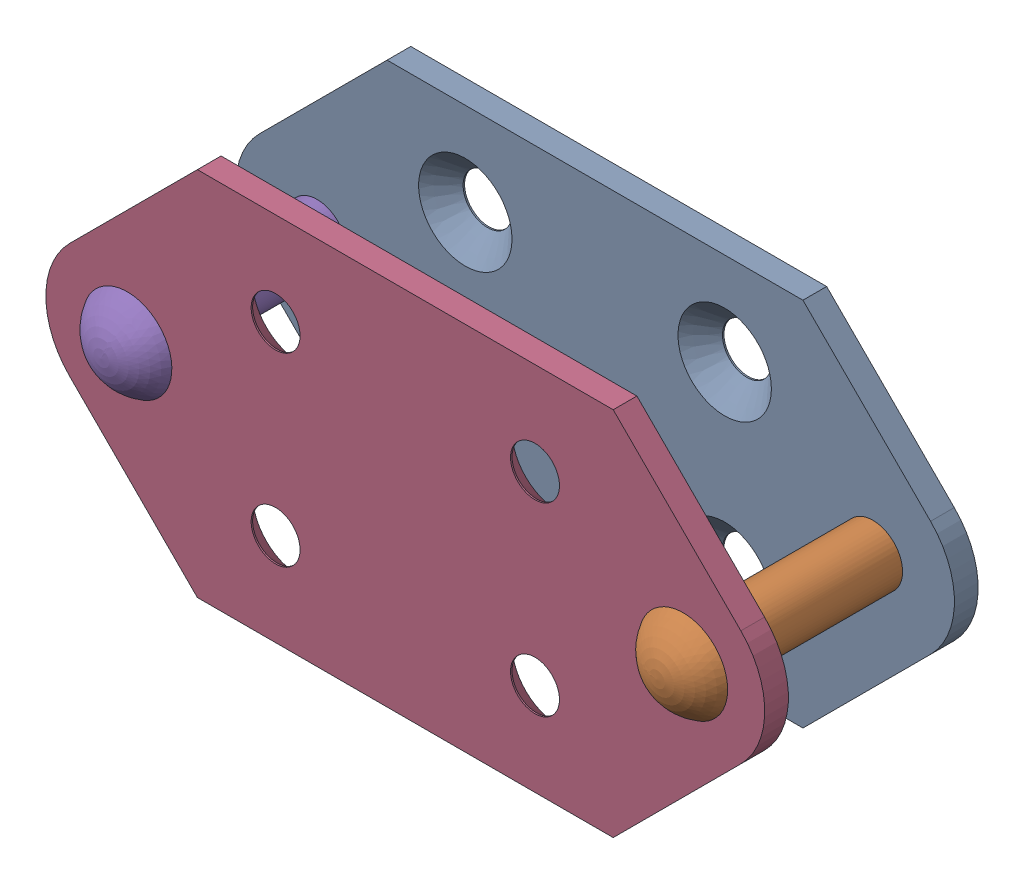
SolidWorks assembly ChainGroup2, configuration Default. Lengths in mm.
Overall size (97 50 36).
6 component instances, 3 part files, 14 mates.
Components (placement in the parent):
- AttachmentLink-1: AttachmentLink [Default] at (75 0 -11.2) x (-1 0 0) z (0 0 -1) size (97 50 3.2)
- Pin-1: Pin [Default] at (75 0 -20) x (0 0 1) z (-0.138868 -0.990311 0) size (36 12 12)
- EStyleRetainingRing-1: EStyleRetainingRing [Default] at (75 0 -14.4) x (-0.984041 -0.177944 0) z (0 0 -1) size (16 14.32 2)
- AttachmentLink-2: AttachmentLink [Default] at (75 0 11.2) x (-1 0 0) z (0 0 1) size (97 50 3.2)
- Pin-2: Pin [Default] at (0 0 -20) x (0 0 1) z (-0.914848 0.403798 0) size (36 12 12)
- EStyleRetainingRing-2: EStyleRetainingRing [Default] at (0 0 -14.4) x (-0.524221 -0.851582 0) z (0 0 -1) size (16 14.32 2)
Mates (geometry in assembly coordinates):
- Concentric1: concentric anti-aligned: cylinder of AttachmentLink-1 through (75 0 -14.4) axis (0 0 1) radius 4; cylinder of AttachmentLink-2 through (75 0 14.4) axis (0 0 -1) radius 4
- Concentric2: concentric anti-aligned: cylinder of AttachmentLink-1 through (0 0 -14.4) axis (0 0 1) radius 4; cylinder of AttachmentLink-2 through (0 0 14.4) axis (0 0 -1) radius 4
- Concentric3: concentric anti-aligned: cylinder of AttachmentLink-1 through (75 0 -14.4) axis (0 0 1) radius 4; cylinder of Pin-1 through (75 0 -20) axis (0 0 -1) radius 4
- Concentric4: concentric anti-aligned: cylinder of AttachmentLink-1 through (0 0 -14.4) axis (0 0 1) radius 4; cylinder of Pin-2 through (0 0 -20) axis (0 0 -1) radius 4
- Coincident2: coincident anti-aligned: plane of Pin-1 through (71.0388 0.5555 14.4) normal (0 0 -1); plane of AttachmentLink-2 through (75 0 14.4) normal (0 0 1)
- Coincident3: coincident anti-aligned: plane of AttachmentLink-2 through (75 0 14.4) normal (0 0 1); plane of Pin-2 through (1.6152 3.6594 14.4) normal (0 0 -1)
- Concentric5: concentric aligned: cylinder of Pin-1 through (75 0 14.4) axis (0 0 1) radius 3; cylinder of PinLock-1 through (75 0 -16.4) axis (0 0 1) radius 3
- Concentric6: concentric aligned: cylinder of Pin-2 through (0 0 14.4) axis (0 0 1) radius 3; cylinder of PinLock-2 through (0 0 -16.4) axis (0 0 1) radius 3
- Coincident4: coincident anti-aligned: plane of Pin-2 through (3.6594 -1.6152 -16.4) normal (0 0 1); plane of PinLock-2 through (-2.7786 -4.4544 -16.4) normal (0 0 -1)
- Coincident5: coincident anti-aligned: plane of Pin-1 through (75.5555 3.9612 -16.4) normal (0 0 1); plane of PinLock-1 through (69.8284 -0.9036 -16.4) normal (0 0 -1)
- Coincident6: coincident anti-aligned: plane of AttachmentLink-1 through (75 0 -14.4) normal (0 0 -1); plane of PinLock-2 through (-2.7786 -4.4544 -14.4) normal (0 0 1)
- Symmetric6: symmetric aligned: plane of AttachmentLink-1 through (75 0 -11.2) normal (0 0 1); plane of AttachmentLink-2 through (75 0 11.2) normal (0 0 -1)
- Symmetric8: symmetric aligned: plane of AttachmentLink-2 through (65.5563 25 14.4) normal (0 1 0); plane of AttachmentLink-2 through (65.5563 -25 14.4) normal (0 -1 0)
- Concentric8: concentric: cylinder of Pin-2 through (0 0 -20) axis (0 0 -1) radius 4
